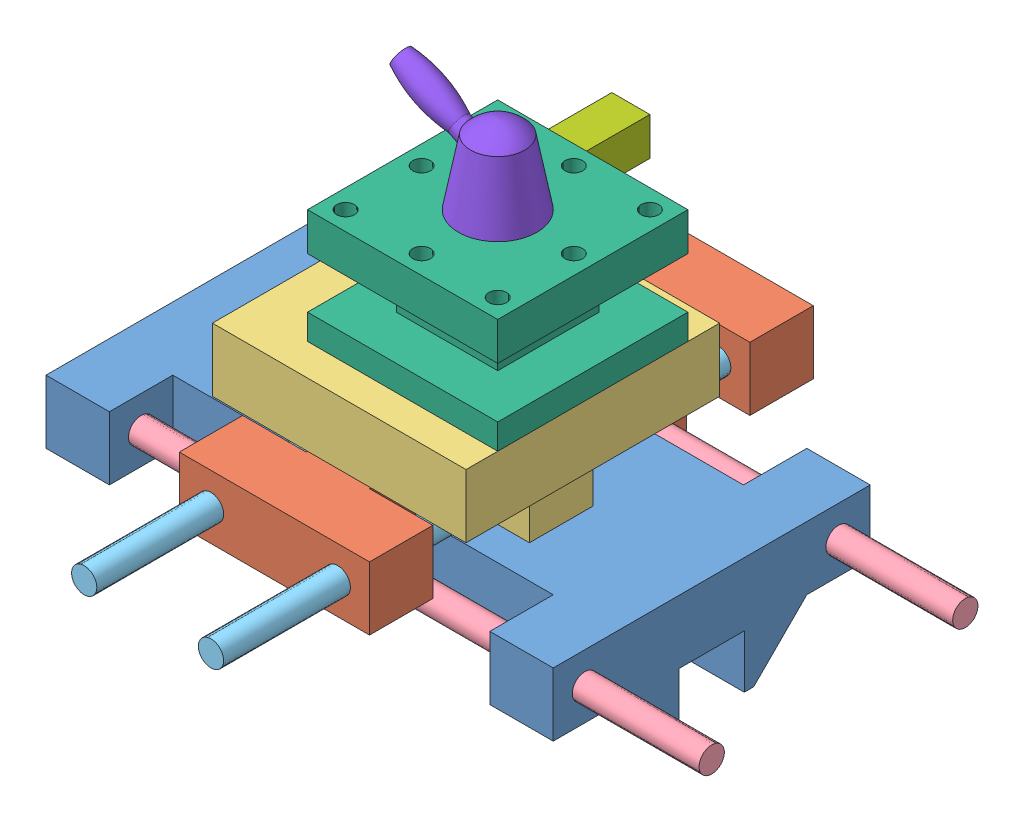
SolidWorks assembly Assem1, configuration Default. Lengths in mm.
Overall size (500 356.59 450).
10 component instances, 8 part files, 20 mates.
Components (placement in the parent):
- base-1: base [Default] at (-59.4281 179.2909 389.6687) size (400 91.94 250)
- slide-1: slide [Default] at (145.6849 179.2909 439.6687) size (150 100 350)
- cross slide-1: cross slide [Default] at (95.6849 229.2909 313.541) x (1 0 0) z (0 -1 0) size (200 200 224)
- 500 rod-1: 500 rod [Default] at (-59.4281 204.2909 414.6687) x (1 0 0) z (0 0.99419 -0.107639) size (500 20 20)
- 500 rod-2: 500 rod [Default] at (-59.4281 204.2909 214.6687) size (500 20 20)
- 450 rod-1: 450 rod [Default] at (220.6849 254.2909 139.6687) x (0 0 1) z (-1 0 0) size (450 20 20)
- 450 rod-2: 450 rod [Default] at (120.6849 254.2909 139.6687) x (0 0 1) z (-1 0 0) size (450 20 20)
- tool post-1: tool post [Default] at (120.6849 329.2909 413.541) size (150 90 150)
- tool holder-1: tool holder [Default] at (120.6849 349.2909 173.541) x (0 0 1) z (-1 0 0) size (200 30 30)
- tightning-1: tightning [Default] at (195.6849 419.2909 338.541) x (0.999951 0 -0.009934) z (0.009934 0 0.999951) size (110.23 74.65 62)
Mates (geometry in assembly coordinates):
- Concentric1: concentric aligned: cylinder of base-1 through (-103.4281 204.2909 414.6687) axis (1 0 0) radius 10; cylinder of slide-1 through (86.6849 204.2909 414.6687) axis (1 0 0) radius 10
- Coincident1: coincident anti-aligned: plane of base-1 through (-59.4281 229.2909 389.6687) normal (0 1 0); plane of slide-1 through (86.6849 229.2909 439.6687) normal (0 -1 0)
- Coincident2: coincident anti-aligned: plane of slide-1 through (195.6849 279.2909 439.6687) normal (0 1 0); plane of cross slide-1 through (95.6849 279.2909 363.541) normal (0 -1 0)
- Concentric3: concentric aligned: cylinder of slide-1 through (220.6849 254.2909 91.6687) axis (0 0 1) radius 10; cylinder of cross slide-1 through (220.6849 254.2909 313.541) axis (0 0 1) radius 10
- Concentric4: concentric anti-aligned: cylinder of base-1 through (-103.4281 204.2909 414.6687) axis (1 0 0) radius 10; cylinder of 500 rod-1 through (440.5719 204.2909 414.6687) axis (-1 0 0) radius 10
- Coincident3: coincident aligned: plane of base-1 through (-59.4281 229.2909 389.6687) normal (-1 0 0); plane of 500 rod-1 through (-59.4281 204.2909 414.6687) normal (-1 0 0)
- Concentric5: concentric anti-aligned: cylinder of base-1 through (-103.4281 204.2909 214.6687) axis (1 0 0) radius 10; cylinder of 500 rod-2 through (440.5719 204.2909 214.6687) axis (-1 0 0) radius 10
- Coincident5: coincident aligned: plane of base-1 through (-59.4281 229.2909 389.6687) normal (-1 0 0); plane of 500 rod-2 through (-59.4281 204.2909 214.6687) normal (-1 0 0)
- Concentric6: concentric anti-aligned: cylinder of slide-1 through (220.6849 254.2909 91.6687) axis (0 0 1) radius 10; cylinder of 450 rod-1 through (220.6849 254.2909 589.6687) axis (0 0 -1) radius 10
- Concentric7: concentric anti-aligned: cylinder of slide-1 through (120.6849 254.2909 91.6687) axis (0 0 1) radius 10; cylinder of 450 rod-2 through (120.6849 254.2909 589.6687) axis (0 0 -1) radius 10
- Coincident6: coincident aligned: plane of slide-1 through (145.6849 179.2909 139.6687) normal (0 0 -1); plane of 450 rod-1 through (220.6849 254.2909 139.6687) normal (0 0 -1)
- Coincident7: coincident aligned: plane of slide-1 through (145.6849 179.2909 139.6687) normal (0 0 -1); plane of 450 rod-2 through (120.6849 254.2909 139.6687) normal (0 0 -1)
- Concentric8: concentric anti-aligned: cylinder of cross slide-1 through (195.6849 453.2909 338.541) axis (0 -1 0) radius 13; cylinder of tool post-1 through (195.6849 251.2909 338.541) axis (0 1 0) radius 13
- Coincident9: coincident anti-aligned: plane of cross slide-1 through (95.6849 329.2909 363.541) normal (0 1 0); plane of tool post-1 through (120.6849 329.2909 413.541) normal (0 -1 0)
- Coincident10: coincident aligned: plane of cross slide-1 through (270.6849 279.2909 313.541) normal (1 0 0); plane of tool post-1 through (270.6849 349.2909 413.541) normal (1 0 0)
- Coincident11: coincident anti-aligned: plane of tool post-1 through (120.6849 349.2909 413.541) normal (0 1 0); plane of tool holder-1 through (120.6849 349.2909 373.541) normal (0 -1 0)
- Coincident13: coincident aligned: plane of tool post-1 through (120.6849 419.2909 263.541) normal (-1 0 0); plane of tool holder-1 through (120.6849 349.2909 373.541) normal (-1 0 0)
- Distance1: distance = 110 mm anti-aligned: plane of tool post-1 through (120.6849 349.2909 263.541) normal (0 0 -1); plane of tool holder-1 through (120.6849 349.2909 373.541) normal (0 0 1)
- Concentric9: concentric anti-aligned: cylinder of cross slide-1 through (195.6849 453.2909 338.541) axis (0 -1 0) radius 13; cylinder of tightning-1 through (195.6849 481.514 338.541) axis (0 1 0) radius 13
- Coincident15: coincident anti-aligned: plane of tool post-1 through (120.6849 419.2909 413.541) normal (0 1 0); plane of tightning-1 through (195.6849 419.2909 338.541) normal (0 -1 0)
